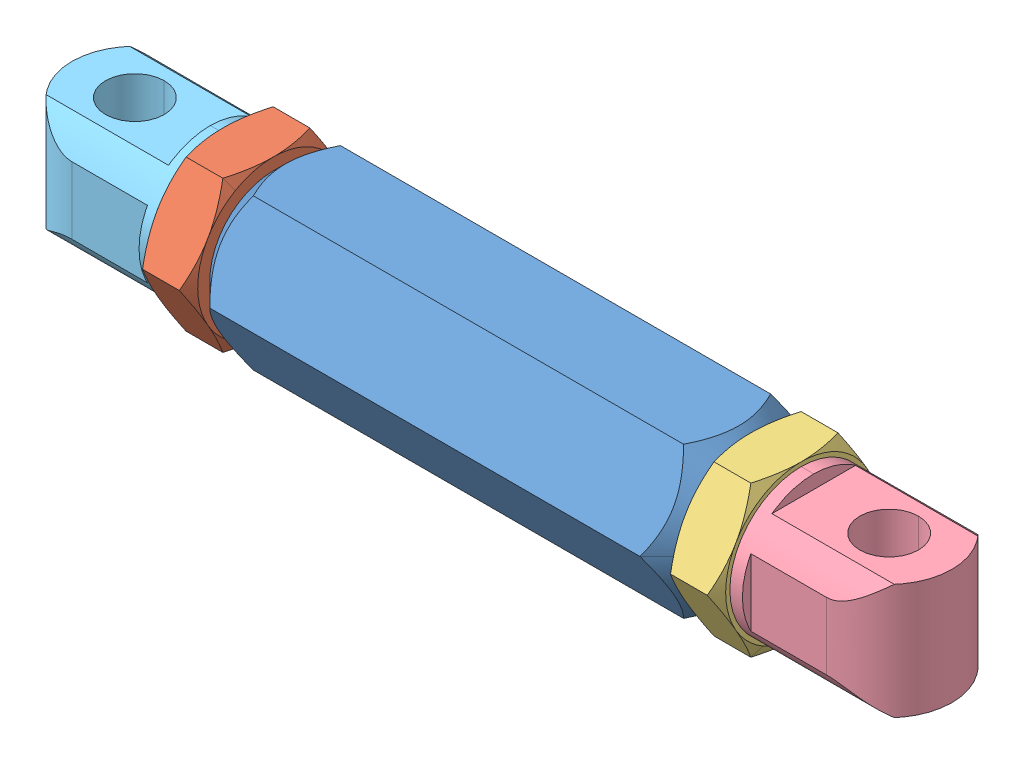
SolidWorks assembly WCP-0248.step, configuration Default. Lengths in mm.
Overall size (55.56 14.29 13.75).
5 component instances, 5 part files, 0 mates.
Components (placement in the parent):
- WCP-0247-001 Rev1.step-1: WCP-0247-001 Rev1.step [Default] at origin size (30.16 11 11)
- NFS-0040_#10-32_jam_nut_left_hand.step-1: NFS-0040_#10-32_jam_nut_left_hand.step [Default] at (-16.6687 0 0) x (0 0.5 -0.866025) z (0 0.866025 0.5) size (9.53 3.18 11)
- NFS-0037_#10-32_jam_nut.step-1: NFS-0037_#10-32_jam_nut.step [Default] at (16.6687 0 0) x (0 0.5 0.866025) z (0 -0.866025 0.5) size (9.53 3.18 11)
- WCP-0248-001 Rev1.step-1: WCP-0248-001 Rev1.step [Default] at (23.8125 0 0) x (0 0 1) z (0 1 0) size (9 25.4 9)
- WCP-0248-002 Rev1.step-1: WCP-0248-002 Rev1.step [Default] at (-23.8125 0 0) x (0 0 -1) z (0 1 0) size (9 25.4 9)
